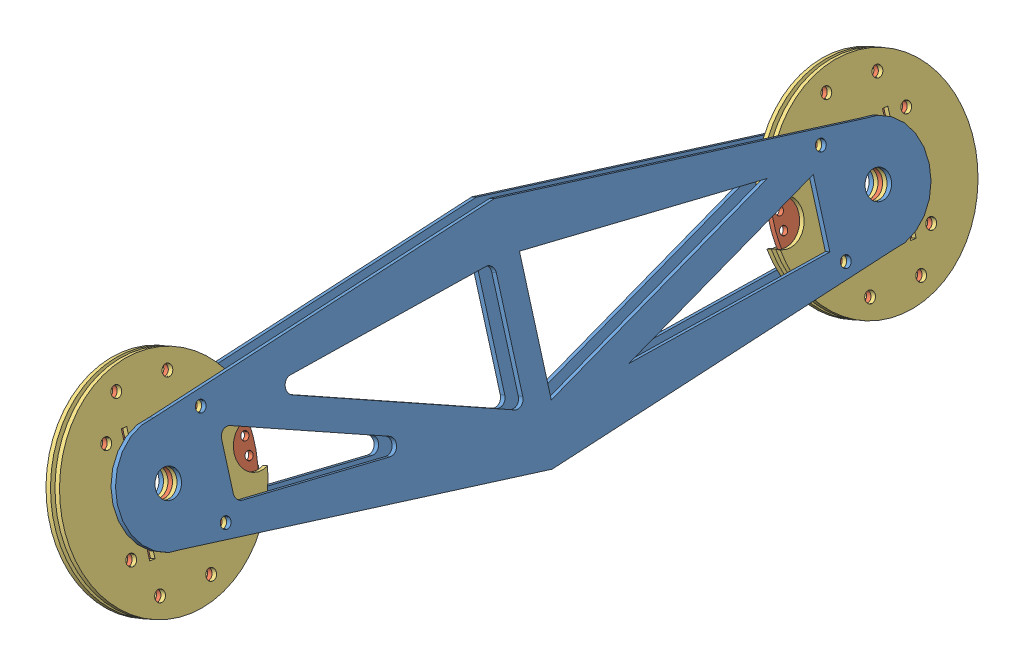
SolidWorks assembly j2, configuration 默认. Lengths in mm.
Overall size (55.07 110.2 364.59).
8 component instances, 3 part files, 14 mates.
Components (placement in the parent):
- 垂直板贴关节盘-1: 垂直板贴关节盘 [默认] at (-42.8884 76.5268 -262.0293) x (0.394275 -0.912764 0.106816) z (-0.918016 -0.396544 0) size (82.1 319.2 2)
- 垂直板贴关节盘-2: 垂直板贴关节盘 [默认] at (-35.5442 79.6992 -262.0293) x (0.394275 -0.912764 0.106816) z (-0.918016 -0.396544 0) size (82.1 319.2 2)
- 关节盘-中间层-1: 关节盘-中间层 [默认] at (-33.794 65.5602 -387.3555) x (-0.394275 0.912764 -0.106816) z (-0.918016 -0.396544 0) size (75 75 2)
- 关节盘-两侧层-1: 关节盘-两侧层 [默认] at (-31.958 66.3533 -387.3555) x (-0.394275 0.912764 -0.106816) z (-0.918016 -0.396544 0) size (79 78.31 2)
- 关节盘-两侧层-2: 关节盘-两侧层 [默认] at (-35.63 64.7671 -387.3555) x (-0.394275 0.912764 -0.106816) z (-0.918016 -0.396544 0) size (79 78.31 2)
- 关节盘-两侧层-3: 关节盘-两侧层 [默认] at (-47.4562 92.1451 -109.7528) x (0.394275 -0.912764 0.106816) z (-0.918016 -0.396544 0) size (79 78.31 2)
- 关节盘-两侧层-4: 关节盘-两侧层 [默认] at (-43.7841 93.7313 -109.7528) x (0.394275 -0.912764 0.106816) z (-0.918016 -0.396544 0) size (79 78.31 2)
- 关节盘-中间层-2: 关节盘-中间层 [默认] at (-45.6201 92.9382 -109.7528) x (0.394275 -0.912764 0.106816) z (-0.918016 -0.396544 0) size (75 75 2)
Mates (geometry in assembly coordinates):
- 同心16: concentric aligned: cylinder of 关节盘-中间层-1 through (-43.3487 82.6361 -371.6672) axis (0.918016 0.396544 0) radius 2.05; cylinder of 关节盘-两侧层-2 through (-45.1847 81.843 -371.6672) axis (0.918016 0.396544 0) radius 2.05
- 同心17: concentric aligned: cylinder of 关节盘-中间层-1 through (-43.3487 82.6361 -371.6672) axis (0.918016 0.396544 0) radius 2.05; cylinder of 关节盘-两侧层-1 through (-41.5126 83.4292 -371.6672) axis (0.918016 0.396544 0) radius 2.05
- 重合33: coincident aligned: circle of 关节盘-中间层-1; circle of 关节盘-两侧层-2
- 重合34: coincident aligned: circle of 关节盘-中间层-1; circle of 关节盘-两侧层-1
- 重合15: coincident aligned: circle of 关节盘-两侧层-3; circle of 关节盘-中间层-2
- 同心11: concentric aligned: cylinder of 关节盘-两侧层-3 through (-41.5736 73.483 -125.4411) axis (0.918016 0.396544 0) radius 2.05; cylinder of 关节盘-中间层-2 through (-39.7375 74.2761 -125.4411) axis (0.918016 0.396544 0) radius 2.05
- 重合16: coincident aligned: circle of 关节盘-两侧层-4; circle of 关节盘-中间层-2
- 同心12: concentric aligned: cylinder of 关节盘-两侧层-4 through (-37.9015 75.0692 -125.4411) axis (0.918016 0.396544 0) radius 2.05; cylinder of 关节盘-中间层-2 through (-39.7375 74.2761 -125.4411) axis (0.918016 0.396544 0) radius 2.05
- 重合71: coincident aligned: circle of 关节盘-两侧层-3; circle of 垂直板贴关节盘-1
- 重合73: coincident aligned: circle of 关节盘-两侧层-4; circle of 垂直板贴关节盘-2
- 重合75: coincident aligned: circle of 垂直板贴关节盘-2; circle of 关节盘-两侧层-1
- 重合76: coincident aligned: circle of 垂直板贴关节盘-2; circle of 关节盘-两侧层-1
- 重合77: coincident aligned: circle of 垂直板贴关节盘-1; circle of 关节盘-两侧层-2
- 重合78: coincident aligned: circle of 垂直板贴关节盘-2; circle of 关节盘-两侧层-4
